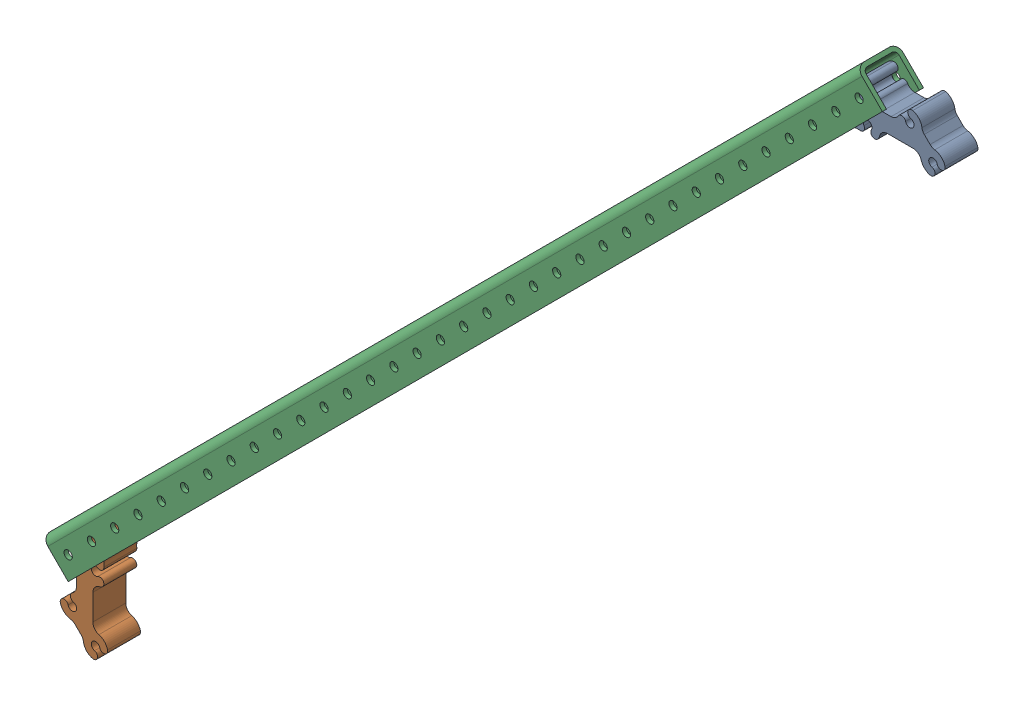
SolidWorks assembly Assem2^harris_chassis, configuration Default. Lengths in mm.
Overall size (694.08 694.08 31.75).
3 component instances, 2 part files, 6 mates.
Components (placement in the parent):
- User Library-Corner Extrusion-1: User Library-Corner Extrusion [Default] at origin size (90.51 36.63 25.4)
- User Library-Corner Extrusion-2: User Library-Corner Extrusion [Default] at (-613.5256 -613.5256 25.4) x (0 -1 0) z (0 0 -1) size (90.51 36.63 25.4)
- C-Base Rail Long-1: C-Base Rail Long [Default] at (-636.0333 -583.4546 21.373) x (0.707107 0.707107 0) z (-0.707107 0.707107 0) size (889 31.75 28.57)
Mates (geometry in assembly coordinates):
- Coincident1: coincident anti-aligned: plane of C-Base Rail Long-1 through (-0.7827 15.875 25.4) normal (0 0 -1); plane of User Library-Corner Extrusion-1 through (17.1778 15.875 25.4) normal (0 0 1)
- Concentric1: concentric anti-aligned: circle of C-Base Rail Long-1; circle of User Library-Corner Extrusion-1
- Concentric2: concentric anti-aligned: circle of C-Base Rail Long-1; circle of User Library-Corner Extrusion-1
- Coincident2: coincident anti-aligned: plane of C-Base Rail Long-1 through (-18.7432 33.8355 0) normal (0 0 1); plane of User Library-Corner Extrusion-2 through (-629.4006 -630.7034 0) normal (0 0 -1)
- Concentric3: concentric aligned: circle of C-Base Rail Long-1; circle of User Library-Corner Extrusion-2
- Concentric4: concentric aligned: circle of C-Base Rail Long-1; circle of User Library-Corner Extrusion-2
